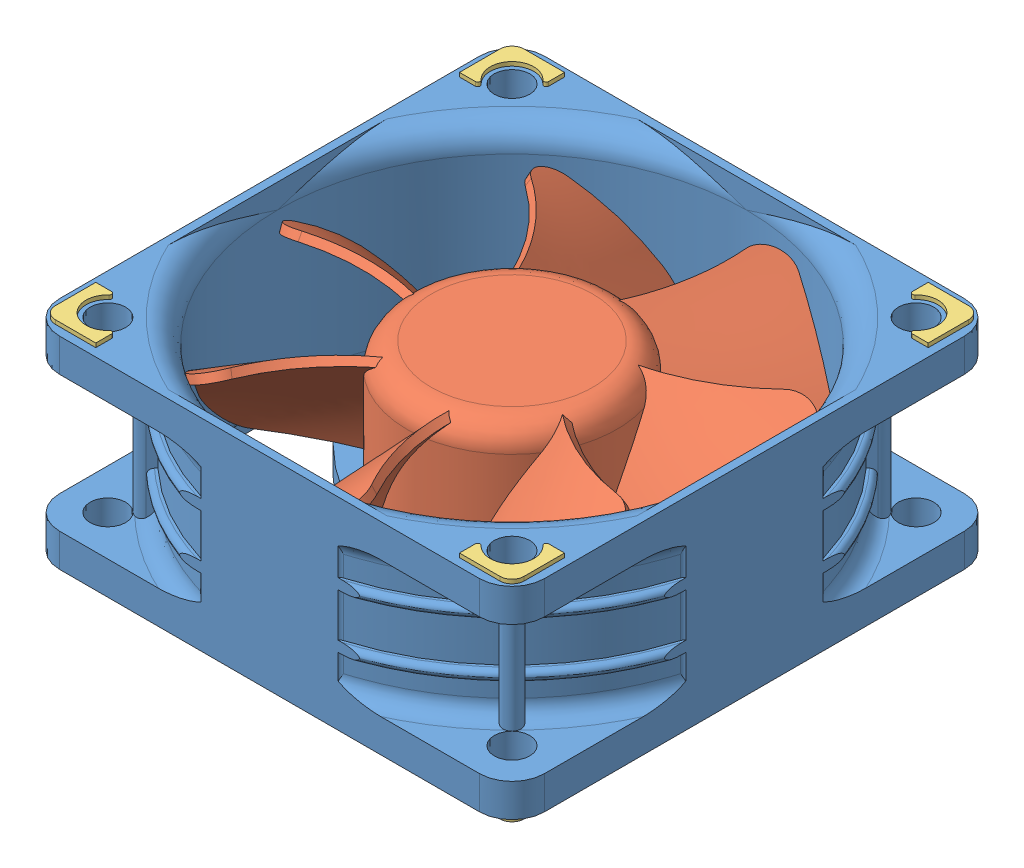
SolidWorks assembly NF A6x25, configuration Default. Lengths in mm.
Overall size (64.02 26 64.02).
4 component instances, 3 part files, 0 mates.
Components (placement in the parent):
- NF A6x25.step-1: NF A6x25.step [Default] at origin size (64.02 26 64.02)
  - Component1.step-1: Component1.step [Default] at (0 13 0) x (1 0 0) z (0 0 -1) size (64.02 25.02 64.02)
  - Component2.step-1: Component2.step [Default] at (0 11 0.7708) x (1 0 0) z (0 0 -1) size (59.47 16.42 59.01)
  - Component3.step-1: Component3.step [Default] at (0 13 0) x (1 0 0) z (0 0 -1) size (58 26 58)
